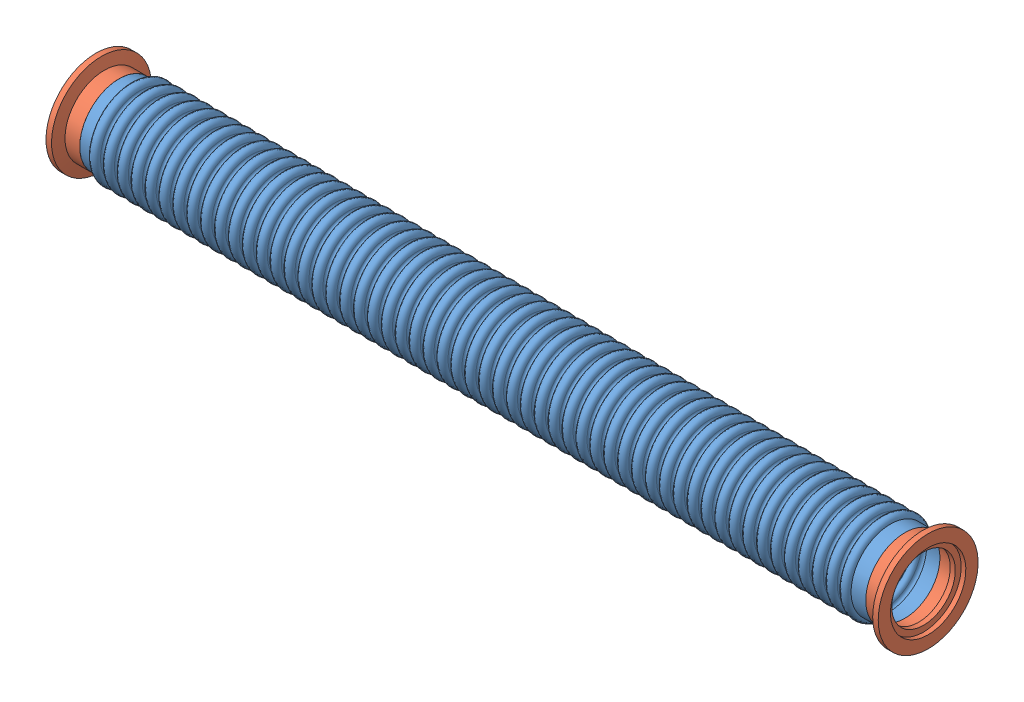
SolidWorks assembly 441524, configuration Default. Lengths in mm.
Overall size (457.2 62.38 62.38).
3 component instances, 2 part files, 4 mates.
Components (placement in the parent):
- 441540-1: 441540 [Default] at (-13.9112 196.4249 329.5512) size (431.8 48.26 48.26)
- 713003-1: 713003 [Default] at (-26.6112 196.4249 329.5512) x (1 0 0) z (0 0.026735 0.999643) size (12.7 54.86 54.86)
- 713003-2: 713003 [Default] at (430.5888 196.4249 329.5512) x (-1 0 0) z (0 -0.988986 0.148011) size (12.7 54.86 54.86)
Mates (geometry in assembly coordinates):
- Concentric1: concentric anti-aligned: cylinder of 441540-1 through (-13.9112 196.4249 329.5512) axis (1 0 0) radius 21.59; cylinder of 713003-1 through (-26.6112 196.4249 329.5512) axis (-1 0 0) radius 21.59
- Coincident1: coincident anti-aligned: plane of 441540-1 through (-13.9112 196.4249 329.5512) normal (-1 0 0); plane of 713003-1 through (-13.9112 215.595 329.0385) normal (1 0 0)
- Concentric2: concentric aligned: cylinder of 441540-1 through (-13.9112 196.4249 329.5512) axis (1 0 0) radius 21.59; cylinder of 713003-2 through (430.5888 196.4249 329.5512) axis (1 0 0) radius 21.59
- Coincident2: coincident: plane of 441540-1 through (417.8888 196.4249 329.5512) normal (1 0 0); plane of 713003-2 through (417.8888 193.5865 310.5854) normal (-1 0 0)
